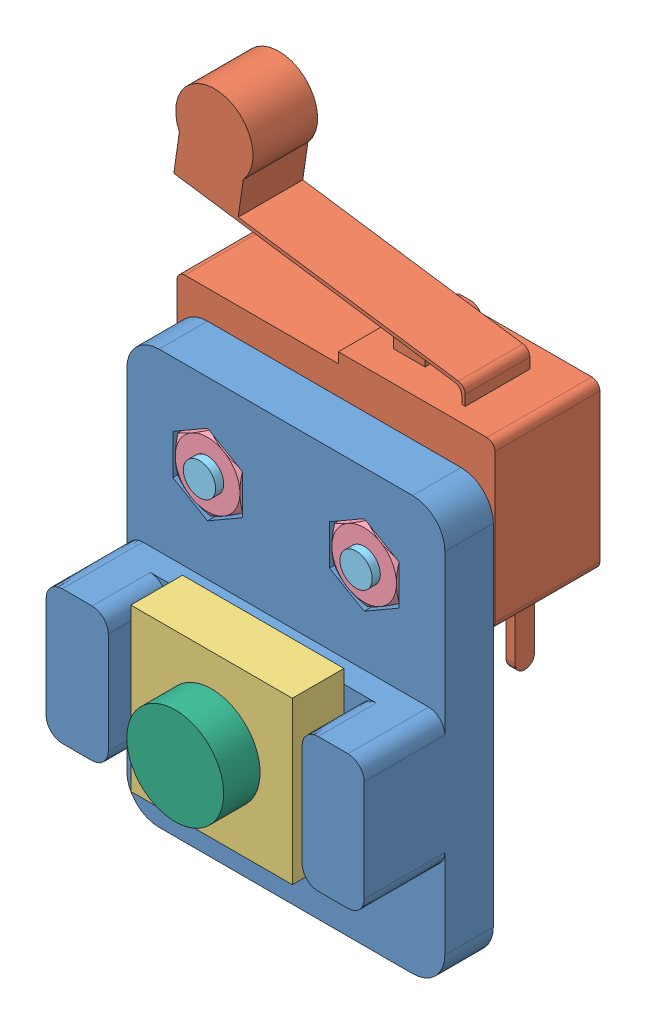
SolidWorks assembly switch_mount_A, configuration По умолчанию. Lengths in mm.
Overall size (20.89 37.34 17.92).
8 component instances, 6 part files, 16 mates.
Components (placement in the parent):
- switch_mount-1: switch_mount [По умолчанию] at origin size (19.7 25.65 8)
- kw4A(S) microswitch-1: kw4A(S) microswitch [Default] at (-18.9571 7.2494 0) x (0 0 -1) z (1 0 0) size (6.5 23.81 20.89)
- square nut thin grade b_din-1: square nut thin grade b_din [Square nut DIN 562 M6 -N] at (8.966 0 4.4) x (-1 0 0) z (0 0 -1) size (10 10 3.2)
- hex nut style 1 gradeab_din-1: hex nut style 1 gradeab_din [Hexagon Nut ISO 4032 - M2 - D - N] at (4.116 9.7744 3) size (4 4.62 1.6)
- hex nut style 1 gradeab_din-2: hex nut style 1 gradeab_din [Hexagon Nut ISO 4032 - M2 - D - N] at (13.816 9.7744 3) x (0.5 0.866025 0) z (0 0 1) size (4 4.62 1.6)
- pan head cross recess screw_din-1: pan head cross recess screw_din [ISO 7045 - M2 x 10 - Z --- 10N] at (13.816 9.7744 -8.1) x (0 0 1) z (-0.194535 0.980896 0) size (11.57 4 4)
- pan head cross recess screw_din-3: pan head cross recess screw_din [ISO 7045 - M2 x 10 - Z --- 10N] at (4.116 9.7744 -8.1) x (0 0 1) z (-0.943448 0.331521 0) size (11.57 4 4)
- countersunk flat head cross recess screw_din-2: countersunk flat head cross recess screw_din [ISO 7046-1 - M6 x 10 - Z --- 10N] at (8.966 0 -0.15) x (0 0 1) z (-0.973089 -0.23043 0) size (10 11.3 11.3)
Mates (geometry in assembly coordinates):
- Концентричный1: concentric: cylinder of switch_mount-1 through (13.816 9.7744 3) axis (0 0 -1) radius 1; cylinder of kw4A(S) microswitch-1 through (13.816 9.7744 -6.5) axis (0 0 1) radius 1.275
- Совпадение1: coincident: plane of switch_mount-1 through (0 0 0) normal (0 0 -1); plane of kw4A(S) microswitch-1 through (-0.284 16.2694 0) normal (0 0 1)
- Концентричный2: concentric: cylinder of switch_mount-1 through (4.116 9.7744 3) axis (0 0 -1) radius 1; cylinder of kw4A(S) microswitch-1 through (4.116 9.7744 -6.5) axis (0 0 1) radius 1.275
- Совпадение4: coincident: plane of switch_mount-1 through (0 0 4.4) normal (0 0 1); plane of square nut thin grade b_din-1 through (13.966 -5 4.4) normal (0 0 -1)
- Параллельность1: parallel: plane of switch_mount-1 through (14.966 0 8) normal (-1 0 0); plane of square nut thin grade b_din-1 through (13.966 -5 7.6) normal (1 0 0)
- Концентричный7: concentric: cylinder of switch_mount-1 through (4.116 9.7744 3) axis (0 0 -1) radius 1; cylinder of hex nut style 1 gradeab_din-1 through (4.116 9.7744 1.4) axis (0 0 1) radius 0.8
- Концентричный8: concentric: cylinder of switch_mount-1 through (13.816 9.7744 3) axis (0 0 -1) radius 1; cylinder of hex nut style 1 gradeab_din-2 through (13.816 9.7744 1.4) axis (0 0 1) radius 0.8
- Параллельность2: parallel: plane of switch_mount-1 through (18.816 0 3) normal (1 0 0); plane of hex nut style 1 gradeab_din-1 through (6.116 10.9291 1.4) normal (1 0 0)
- Параллельность3: parallel: plane of switch_mount-1 through (18.816 0 3) normal (1 0 0); plane of hex nut style 1 gradeab_din-2 through (15.816 8.6197 1.4) normal (1 0 0)
- Совпадение7: coincident: plane of switch_mount-1 through (0 0 1.4) normal (0 0 1); plane of hex nut style 1 gradeab_din-1 through (4.116 12.0838 1.4) normal (0 0 -1)
- Совпадение8: coincident: plane of switch_mount-1 through (0 0 1.4) normal (0 0 1); plane of hex nut style 1 gradeab_din-2 through (11.816 10.9291 1.4) normal (0 0 -1)
- Концентричный9: concentric: cylinder of kw4A(S) microswitch-1 through (13.816 9.7744 -6.5) axis (0 0 1) radius 1.275; cylinder of pan head cross recess screw_din-1 through (13.816 9.7744 -33.5) axis (0 0 -1) radius 1
- Совпадение9: coincident: plane of kw4A(S) microswitch-1 through (-0.284 16.2694 -6.5) normal (0 0 -1); plane of pan head cross recess screw_din-1 through (14.7969 9.9689 -6.5) normal (0 0 1)
- Концентричный12: concentric: cylinder of kw4A(S) microswitch-1 through (4.116 9.7744 -6.5) axis (0 0 1) radius 1.275; cylinder of pan head cross recess screw_din-3 through (4.116 9.7744 -33.5) axis (0 0 -1) radius 1
- Совпадение11: coincident: plane of kw4A(S) microswitch-1 through (-0.284 16.2694 -6.5) normal (0 0 -1); plane of pan head cross recess screw_din-3 through (4.4475 10.7178 -6.5) normal (0 0 1)
- Совпадение13: coincident: cone of switch_mount-1 through (8.966 0 0) axis (0 0 1); cone of countersunk flat head cross recess screw_din-2 through (8.966 0 0.5) axis (0 0 1)
